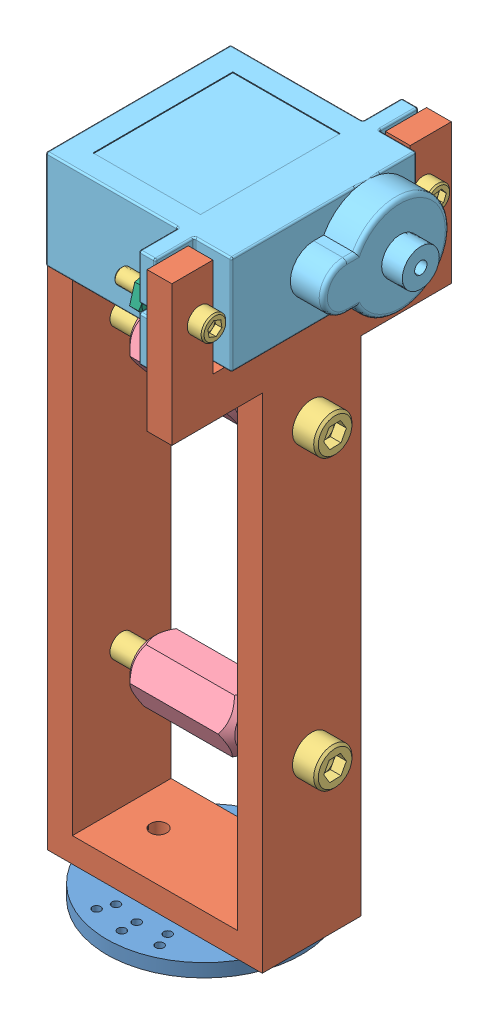
SolidWorks assembly bottom servo assem, configuration Default. Lengths in mm.
Overall size (36.89 82.63 34.06).
13 component instances, 6 part files, 25 mates.
Components (placement in the parent):
- Micro Servo Horn Round-1: Micro Servo Horn Round [Default] at (9.7817 11.4557 18.2521) size (23.65 4.35 23.65)
- bottom servo arm-1: bottom servo arm [Default] at (9.7714 16.0686 18.2394) x (0.999997 0 -0.002296) z (-0.002296 0 -0.999997) size (26 78 34)
- socket head cap screw_ai-1: socket head cap screw_ai [HX-SHCS 0.112-40x0.5x0.5-N] at (25.6162 33.0686 18.203) x (-0.999997 0 0.002296) z (-0.000065 -0.999594 -0.028493) size (15.54 4.65 4.65)
- socket head cap screw_ai-2: socket head cap screw_ai [HX-SHCS 0.112-40x0.5x0.5-N] at (25.6162 68.0686 18.203) x (-0.999997 0 0.002296) z (-0.000065 -0.999594 -0.028493) size (15.54 4.65 4.65)
- 25x.5 Aluminum Hex Female Female Standoff-1: 25x.5 Aluminum Hex Female Female Standoff [Default] at (9.7714 68.0686 18.2394) x (-0.002123 -0.380865 -0.924628) z (0.999997 0 -0.002296) size (6.35 8.06 12.7)
- 25x.5 Aluminum Hex Female Female Standoff-2: 25x.5 Aluminum Hex Female Female Standoff [Default] at (9.7714 33.0686 18.2394) x (-0.001939 -0.535745 -0.844378) z (0.999997 0 -0.002296) size (6.35 8.06 12.7)
- Micro Servo SG92R 180-1: Micro Servo SG92R 180 [Valor predeterminado] at (17.7714 85.5949 18.221) x (0.002296 0 0.999997) z (0 1 0) size (32 29 12)
- socket head cap screw_ai-3: socket head cap screw_ai [HX-SHCS 0.112-40x0.5x0.5-N] at (-6.0733 68.0686 18.2758) x (0.999997 0 -0.002296) z (-0.000307 -0.991051 -0.133483) size (15.54 4.65 4.65)
- socket head cap screw_ai-4: socket head cap screw_ai [HX-SHCS 0.112-40x0.5x0.5-N] at (-6.0733 33.0686 18.2758) x (0.999997 0 -0.002296) z (-0.000307 -0.991051 -0.133483) size (15.54 4.65 4.65)
- socket head cap screw_ai-5: socket head cap screw_ai [HX-SHCS 0.073-72x0.375x0.375-N] at (24.6569 85.5949 31.8303) x (-0.999997 0 0.002296) z (-0.001436 -0.780194 -0.625536) size (11.38 3 3)
- socket head cap screw_ai-6: socket head cap screw_ai [HX-SHCS 0.073-72x0.375x0.375-N] at (24.5943 85.5949 4.5803) x (-0.999997 0 0.002296) z (0.000316 0.990504 0.137486) size (11.38 3 3)
- machine screw nut hex_ai-3: machine screw nut hex_ai [MSHXNUT 0.073-72-S-N] at (17.8027 85.5949 31.846) x (-0.002207 -0.276755 -0.960938) z (0.999997 0 -0.002296) size (3.96 4.58 1.27)
- machine screw nut hex_ai-4: machine screw nut hex_ai [MSHXNUT 0.073-72-S-N] at (17.7401 85.5949 4.5961) x (-0.001605 -0.71523 -0.698887) z (0.999997 0 -0.002296) size (3.96 4.58 1.27)
Mates (geometry in assembly coordinates):
- Coincident3: coincident anti-aligned: plane of Micro Servo Horn Round-1 through (9.7817 13.0686 18.2521) normal (0 1 0); plane of bottom servo arm-1 through (9.7714 13.0686 18.2394) normal (0 -1 0)
- Concentric4: concentric aligned: circle of Micro Servo Horn Round-1; circle of bottom servo arm-1
- Coincident12: coincident anti-aligned: plane of bottom servo arm-1 through (22.7576 13.0686 12.2096) normal (0.999997 0 -0.002296); plane of socket head cap screw_ai-1 through (22.7661 33.1348 15.8864) normal (-0.999997 0 0.002296)
- Concentric7: concentric anti-aligned: cylinder of bottom servo arm-1 through (26.7714 33.0686 18.2004) axis (-0.999997 0 0.002296) radius 1.425; cylinder of socket head cap screw_ai-1 through (57.3661 33.0686 18.1301) axis (0.999997 0 -0.002296) radius 1.4224
- Coincident15: coincident anti-aligned: plane of bottom servo arm-1 through (22.7576 13.0686 12.2096) normal (0.999997 0 -0.002296); plane of socket head cap screw_ai-2 through (22.7661 68.1348 15.8864) normal (-0.999997 0 0.002296)
- Concentric9: concentric anti-aligned: cylinder of bottom servo arm-1 through (26.7714 68.0686 18.2004) axis (-0.999997 0 0.002296) radius 1.425; cylinder of socket head cap screw_ai-2 through (57.3661 68.0686 18.1301) axis (0.999997 0 -0.002296) radius 1.4224
- Concentric10: concentric aligned: cylinder of socket head cap screw_ai-1 through (57.3661 33.0686 18.1301) axis (0.999997 0 -0.002296) radius 1.4224; cylinder of 25x.5 Aluminum Hex Female Female Standoff-2 through (16.1214 33.0686 18.2248) axis (0.999997 0 -0.002296) radius 1.0287
- Width1: width anti-aligned: plane of bottom servo arm-1 through (-0.2423 91.0686 12.2624) normal (0.999997 0 -0.002296); plane of 25x.5 Aluminum Hex Female Female Standoff-2 through (19.7576 91.0686 12.2165) normal (-0.999997 0 0.002296); plane of bottom servo arm-1 through (3.4215 33.0686 18.254) normal (-0.999997 0 0.002296); plane of 25x.5 Aluminum Hex Female Female Standoff-2 through (16.1214 33.0686 18.2248) normal (0.999997 0 -0.002296)
- Concentric11: concentric aligned: cylinder of socket head cap screw_ai-2 through (57.3661 68.0686 18.1301) axis (0.999997 0 -0.002296) radius 1.4224; cylinder of 25x.5 Aluminum Hex Female Female Standoff-1 through (16.1214 68.0686 18.2248) axis (0.999997 0 -0.002296) radius 1.0287
- Width2: width anti-aligned: plane of bottom servo arm-1 through (19.7576 91.0686 12.2165) normal (-0.999997 0 0.002296); plane of 25x.5 Aluminum Hex Female Female Standoff-1 through (-0.2423 91.0686 12.2624) normal (0.999997 0 -0.002296); plane of bottom servo arm-1 through (16.1214 68.0686 18.2248) normal (0.999997 0 -0.002296); plane of 25x.5 Aluminum Hex Female Female Standoff-1 through (3.4215 68.0686 18.254) normal (-0.999997 0 0.002296)
- Coincident17: coincident anti-aligned: plane of bottom servo arm-1 through (19.7576 91.0686 12.2165) normal (-0.999997 0 0.002296); plane of Micro Servo SG92R 180-1 through (19.7401 85.5949 4.5915) normal (0.999997 0 -0.002296)
- Concentric12: concentric aligned: cylinder of bottom servo arm-1 through (26.7714 68.0686 18.2004) axis (-0.999997 0 0.002296) radius 1.425; cylinder of socket head cap screw_ai-3 through (-37.8232 68.0686 18.3487) axis (-0.999997 0 0.002296) radius 1.4224
- Coincident19: coincident anti-aligned: plane of bottom servo arm-1 through (-3.2423 13.0686 12.2693) normal (-0.999997 0 0.002296); plane of socket head cap screw_ai-3 through (-3.2232 67.7584 20.5726) normal (0.999997 0 -0.002296)
- Concentric13: concentric aligned: cylinder of bottom servo arm-1 through (26.7714 33.0686 18.2004) axis (-0.999997 0 0.002296) radius 1.425; cylinder of socket head cap screw_ai-4 through (-37.8232 33.0686 18.3487) axis (-0.999997 0 0.002296) radius 1.4224
- Coincident20: coincident anti-aligned: plane of bottom servo arm-1 through (-3.2423 13.0686 12.2693) normal (-0.999997 0 0.002296); plane of socket head cap screw_ai-4 through (-3.2232 32.7584 20.5726) normal (0.999997 0 -0.002296)
- Width3: width aligned: plane of Micro Servo SG92R 180-1 through (1.7973 79.5949 29.5078) normal (0.002296 0 0.999997); plane of bottom servo arm-1 through (1.7456 79.5949 7.0078) normal (-0.002296 0 -0.999997); plane of Micro Servo SG92R 180-1 through (-3.2147 13.0686 24.2693) normal (0.002296 0 0.999997); plane of bottom servo arm-1 through (-3.2423 13.0686 12.2693) normal (-0.002296 0 -0.999997)
- Concentric14: concentric aligned: cylinder of bottom servo arm-1 through (19.7401 85.5949 4.5915) axis (0.999997 0 -0.002296) radius 1; cylinder of socket head cap screw_ai-6 through (56.3442 85.5949 4.5074) axis (0.999997 0 -0.002296) radius 0.9271
- Coincident21: coincident anti-aligned: plane of bottom servo arm-1 through (22.7576 13.0686 12.2096) normal (0.999997 0 -0.002296); plane of socket head cap screw_ai-6 through (22.7435 85.3889 6.069) normal (-0.999997 0 0.002296)
- Concentric15: concentric aligned: cylinder of bottom servo arm-1 through (19.8027 85.5949 31.8414) axis (0.999997 0 -0.002296) radius 1; cylinder of socket head cap screw_ai-5 through (56.4068 85.5949 31.7574) axis (0.999997 0 -0.002296) radius 0.9271
- Coincident22: coincident anti-aligned: plane of bottom servo arm-1 through (22.7576 13.0686 12.2096) normal (0.999997 0 -0.002296); plane of socket head cap screw_ai-5 through (22.8 86.5323 30.6653) normal (-0.999997 0 0.002296)
- Concentric16: concentric aligned: circle of socket head cap screw_ai-5; cylinder of machine screw nut hex_ai-3 through (16.5327 85.5949 31.8489) axis (0.999997 0 -0.002296) radius 0.7556
- Coincident23: coincident anti-aligned: plane of Micro Servo SG92R 180-1 through (17.8027 85.5949 31.846) normal (-0.999997 0 0.002296); plane of machine screw nut hex_ai-3 through (17.8115 86.6915 35.6536) normal (0.999997 0 -0.002296)
- Concentric17: concentric aligned: cylinder of socket head cap screw_ai-6 through (56.3442 85.5949 4.5074) axis (0.999997 0 -0.002296) radius 0.9271; cylinder of machine screw nut hex_ai-4 through (16.4701 85.5949 4.599) axis (0.999997 0 -0.002296) radius 0.7556
- Coincident27: coincident anti-aligned: plane of Micro Servo SG92R 180-1 through (17.7401 85.5949 4.5961) normal (-0.999997 0 0.002296); plane of machine screw nut hex_ai-4 through (17.7465 88.4289 7.3654) normal (0.999997 0 -0.002296)
- Concentric18: concentric anti-aligned: cylinder of Micro Servo SG92R 180-1 through (19.8027 85.5949 31.8414) axis (-0.999997 0 0.002296) radius 1; cylinder of socket head cap screw_ai-5 through (56.4068 85.5949 31.7574) axis (0.999997 0 -0.002296) radius 0.9271
